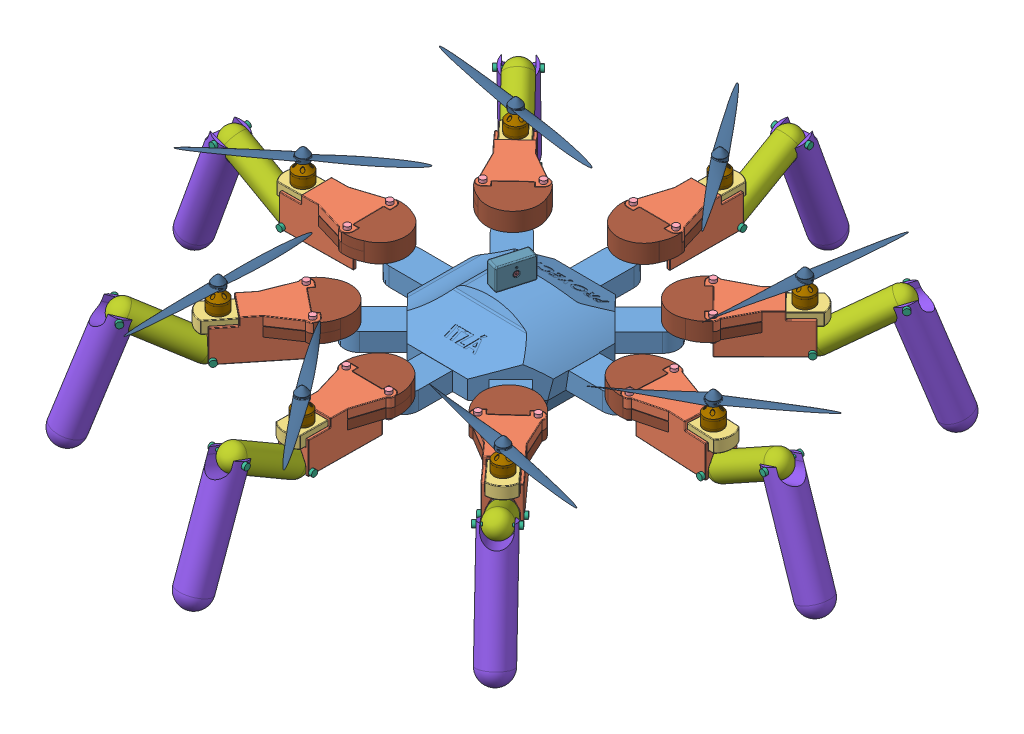
SolidWorks assembly Ensamblaje1, configuration Predeterminado. Lengths in mm.
Overall size (1097.39 246.99 1093.05).
121 component instances, 14 part files, 23 mates.
Components (placement in the parent):
- Cuerpo-1: Cuerpo [Predeterminado] at (-9.0691 -13.0593 180.3619) size (400 129.05 400)
- Sistema de brazo V2-1: Sistema de brazo V2 [Predeterminado] at (128.9081 16.0029 481.489) x (-0.009594 0 0.999954) z (-0.999954 0 -0.009594) size (372.38 235.23 205.09)
  - Brazo1-1: Brazo1 [Predeterminado] at (-6.6953 0.9378 140) size (130.88 65.06 90)
  - Brazo2-1: Brazo2 [Predeterminado] at (-20.6953 5.9378 140) size (180.03 20 40)
  - UnionB1Cuerpo-1: UnionB1Cuerpo [Predeterminado] at (-66.6953 15.9378 105) x (0 1 0) z (0 0 1) size (40 10 10)
  - UnionB1Cuerpo-2: UnionB1Cuerpo [Predeterminado] at (-66.6953 15.9378 175) x (0 1 0) z (-0.093327 0 0.995636) size (40 10 10)
  - TornilloSinFin-1: TornilloSinFin [Predeterminado] at (-26.6953 14.2204 138.1832) x (-1 0 0) z (0 0.686954 0.726701) size (180.05 11.57 10.06)
  - UnionB1P1-1: UnionB1P1 [Predeterminado] at (48.3047 -29.0622 140) x (0 0 -1) z (0.999335 0.036466 0) size (60 10 10)
  - Pierna1V2-1: Pierna1V2 [Predeterminado] at (165.0941 38.3661 140) x (-0.866025 -0.5 0) z (0 0 1) size (150 40 40)
  - Pierna2V2-2: Pierna2V2 [Predeterminado] at (209.6756 -114.1116 140) x (-0.33546 0.942054 0) z (0 0 1) size (200 50 50)
  - UnionB1P1-2: UnionB1P1 [Predeterminado] at (157.0358 33.7137 140) x (0 0 1) z (0.770088 -0.637938 0) size (60 10 10)
  - Motor-1: Motor [Predeterminado] at (39.3047 35.1507 140) x (0.664179 0 0.747574) z (-0.747574 0 0.664179) size (30.15 36.5 30.15)
  - Helise-1: Helise [Predeterminado] at (39.3047 61.4393 140) x (0.608985 0 0.793182) z (-0.793182 0 0.608985) size (28.24 20.07 300)
  - Pinza-1: Pinza [Predeterminado] at (-75.6905 0.9378 140) size (116.44 30 90.88)
- Sistema de brazo V2-2: Sistema de brazo V2 [Predeterminado] at (301.8779 16.0029 303.7493) x (0.668212 0 0.743971) z (-0.743971 0 0.668212) size (372.38 235.23 205.09)
  - Brazo1-1: Brazo1 [Predeterminado] at (-6.6953 0.9378 140) size (130.88 65.06 90)
  - Brazo2-1: Brazo2 [Predeterminado] at (-20.6953 5.9378 140) size (180.03 20 40)
  - UnionB1Cuerpo-1: UnionB1Cuerpo [Predeterminado] at (-66.6953 15.9378 105) x (0 1 0) z (0 0 1) size (40 10 10)
  - UnionB1Cuerpo-2: UnionB1Cuerpo [Predeterminado] at (-66.6953 15.9378 175) x (0 1 0) z (-0.093327 0 0.995636) size (40 10 10)
  - TornilloSinFin-1: TornilloSinFin [Predeterminado] at (-26.6953 14.2204 138.1832) x (-1 0 0) z (0 0.686954 0.726701) size (180.05 11.57 10.06)
  - UnionB1P1-1: UnionB1P1 [Predeterminado] at (48.3047 -29.0622 140) x (0 0 -1) z (0.999335 0.036466 0) size (60 10 10)
  - Pierna1V2-1: Pierna1V2 [Predeterminado] at (165.0941 38.3661 140) x (-0.866025 -0.5 0) z (0 0 1) size (150 40 40)
  - Pierna2V2-2: Pierna2V2 [Predeterminado] at (209.6756 -114.1116 140) x (-0.33546 0.942054 0) z (0 0 1) size (200 50 50)
  - UnionB1P1-2: UnionB1P1 [Predeterminado] at (157.0358 33.7137 140) x (0 0 1) z (0.770088 -0.637938 0) size (60 10 10)
  - Motor-1: Motor [Predeterminado] at (39.3047 35.1507 140) x (0.664179 0 0.747574) z (-0.747574 0 0.664179) size (30.15 36.5 30.15)
  - Helise-1: Helise [Predeterminado] at (39.3047 61.4393 140) x (0.608985 0 0.793182) z (-0.793182 0 0.608985) size (28.24 20.07 300)
  - Pinza-1: Pinza [Predeterminado] at (-75.6905 0.9378 140) size (116.44 30 90.88)
- Sistema de brazo V2-3: Sistema de brazo V2 [Predeterminado] at (297.6452 16.0029 47.3589) x (0.998722 0 0.050534) z (-0.050534 0 0.998722) size (372.38 235.23 205.09)
  - Brazo1-1: Brazo1 [Predeterminado] at (-6.6953 0.9378 140) size (130.88 65.06 90)
  - Brazo2-1: Brazo2 [Predeterminado] at (-20.6953 5.9378 140) size (180.03 20 40)
  - UnionB1Cuerpo-1: UnionB1Cuerpo [Predeterminado] at (-66.6953 15.9378 105) x (0 1 0) z (0 0 1) size (40 10 10)
  - UnionB1Cuerpo-2: UnionB1Cuerpo [Predeterminado] at (-66.6953 15.9378 175) x (0 1 0) z (-0.093327 0 0.995636) size (40 10 10)
  - TornilloSinFin-1: TornilloSinFin [Predeterminado] at (-26.6953 14.2204 138.1832) x (-1 0 0) z (0 0.686954 0.726701) size (180.05 11.57 10.06)
  - UnionB1P1-1: UnionB1P1 [Predeterminado] at (48.3047 -29.0622 140) x (0 0 -1) z (0.999335 0.036466 0) size (60 10 10)
  - Pierna1V2-1: Pierna1V2 [Predeterminado] at (165.0941 38.3661 140) x (-0.866025 -0.5 0) z (0 0 1) size (150 40 40)
  - Pierna2V2-2: Pierna2V2 [Predeterminado] at (209.6756 -114.1116 140) x (-0.33546 0.942054 0) z (0 0 1) size (200 50 50)
  - UnionB1P1-2: UnionB1P1 [Predeterminado] at (157.0358 33.7137 140) x (0 0 1) z (0.770088 -0.637938 0) size (60 10 10)
  - Motor-1: Motor [Predeterminado] at (39.3047 35.1507 140) x (0.664179 0 0.747574) z (-0.747574 0 0.664179) size (30.15 36.5 30.15)
  - Helise-1: Helise [Predeterminado] at (39.3047 61.4393 140) x (0.608985 0 0.793182) z (-0.793182 0 0.608985) size (28.24 20.07 300)
  - Pinza-1: Pinza [Predeterminado] at (-75.6905 0.9378 140) size (116.44 30 90.88)
- Sistema de brazo V2-4: Sistema de brazo V2 [Predeterminado] at (105.4375 16.0029 -130.0624) x (0.710551 0 -0.703646) z (0.703646 0 0.710551) size (372.38 235.23 205.09)
  - Brazo1-1: Brazo1 [Predeterminado] at (-6.6953 0.9378 140) size (130.88 65.06 90)
  - Brazo2-1: Brazo2 [Predeterminado] at (-20.6953 5.9378 140) size (180.03 20 40)
  - UnionB1Cuerpo-1: UnionB1Cuerpo [Predeterminado] at (-66.6953 15.9378 105) x (0 1 0) z (0 0 1) size (40 10 10)
  - UnionB1Cuerpo-2: UnionB1Cuerpo [Predeterminado] at (-66.6953 15.9378 175) x (0 1 0) z (-0.093327 0 0.995636) size (40 10 10)
  - TornilloSinFin-1: TornilloSinFin [Predeterminado] at (-26.6953 14.2204 138.1832) x (-1 0 0) z (0 0.686954 0.726701) size (180.05 11.57 10.06)
  - UnionB1P1-1: UnionB1P1 [Predeterminado] at (48.3047 -29.0622 140) x (0 0 -1) z (0.999335 0.036466 0) size (60 10 10)
  - Pierna1V2-1: Pierna1V2 [Predeterminado] at (165.0941 38.3661 140) x (-0.866025 -0.5 0) z (0 0 1) size (150 40 40)
  - Pierna2V2-2: Pierna2V2 [Predeterminado] at (209.6756 -114.1116 140) x (-0.33546 0.942054 0) z (0 0 1) size (200 50 50)
  - UnionB1P1-2: UnionB1P1 [Predeterminado] at (157.0358 33.7137 140) x (0 0 1) z (0.770088 -0.637938 0) size (60 10 10)
  - Motor-1: Motor [Predeterminado] at (39.3047 35.1507 140) x (0.664179 0 0.747574) z (-0.747574 0 0.664179) size (30.15 36.5 30.15)
  - Helise-1: Helise [Predeterminado] at (39.3047 61.4393 140) x (0.608985 0 0.793182) z (-0.793182 0 0.608985) size (28.24 20.07 300)
  - Pinza-1: Pinza [Predeterminado] at (-75.6905 0.9378 140) size (116.44 30 90.88)
- Sistema de brazo V2-5: Sistema de brazo V2 [Predeterminado] at (-147.6038 16.0029 -120.1096) x (0.004882 0 -0.999988) z (0.999988 0 0.004882) size (372.38 235.23 205.09)
  - Brazo1-1: Brazo1 [Predeterminado] at (-6.6953 0.9378 140) size (130.88 65.06 90)
  - Brazo2-1: Brazo2 [Predeterminado] at (-20.6953 5.9378 140) size (180.03 20 40)
  - UnionB1Cuerpo-1: UnionB1Cuerpo [Predeterminado] at (-66.6953 15.9378 105) x (0 1 0) z (0 0 1) size (40 10 10)
  - UnionB1Cuerpo-2: UnionB1Cuerpo [Predeterminado] at (-66.6953 15.9378 175) x (0 1 0) z (-0.093327 0 0.995636) size (40 10 10)
  - TornilloSinFin-1: TornilloSinFin [Predeterminado] at (-26.6953 14.2204 138.1832) x (-1 0 0) z (0 0.686954 0.726701) size (180.05 11.57 10.06)
  - UnionB1P1-1: UnionB1P1 [Predeterminado] at (48.3047 -29.0622 140) x (0 0 -1) z (0.999335 0.036466 0) size (60 10 10)
  - Pierna1V2-1: Pierna1V2 [Predeterminado] at (165.0941 38.3661 140) x (-0.866025 -0.5 0) z (0 0 1) size (150 40 40)
  - Pierna2V2-2: Pierna2V2 [Predeterminado] at (209.6756 -114.1116 140) x (-0.33546 0.942054 0) z (0 0 1) size (200 50 50)
  - UnionB1P1-2: UnionB1P1 [Predeterminado] at (157.0358 33.7137 140) x (0 0 1) z (0.770088 -0.637938 0) size (60 10 10)
  - Motor-1: Motor [Predeterminado] at (39.3047 35.1507 140) x (0.664179 0 0.747574) z (-0.747574 0 0.664179) size (30.15 36.5 30.15)
  - Helise-1: Helise [Predeterminado] at (39.3047 61.4393 140) x (0.608985 0 0.793182) z (-0.793182 0 0.608985) size (28.24 20.07 300)
  - Pinza-1: Pinza [Predeterminado] at (-75.6905 0.9378 140) size (116.44 30 90.88)
- Sistema de brazo V2-6: Sistema de brazo V2 [Predeterminado] at (-319.7933 16.0029 61.6784) x (-0.687171 0 -0.726496) z (0.726496 0 -0.687171) size (372.38 235.23 205.09)
  - Brazo1-1: Brazo1 [Predeterminado] at (-6.6953 0.9378 140) size (130.88 65.06 90)
  - Brazo2-1: Brazo2 [Predeterminado] at (-20.6953 5.9378 140) size (180.03 20 40)
  - UnionB1Cuerpo-1: UnionB1Cuerpo [Predeterminado] at (-66.6953 15.9378 105) x (0 1 0) z (0 0 1) size (40 10 10)
  - UnionB1Cuerpo-2: UnionB1Cuerpo [Predeterminado] at (-66.6953 15.9378 175) x (0 1 0) z (-0.093327 0 0.995636) size (40 10 10)
  - TornilloSinFin-1: TornilloSinFin [Predeterminado] at (-26.6953 14.2204 138.1832) x (-1 0 0) z (0 0.686954 0.726701) size (180.05 11.57 10.06)
  - UnionB1P1-1: UnionB1P1 [Predeterminado] at (48.3047 -29.0622 140) x (0 0 -1) z (0.999335 0.036466 0) size (60 10 10)
  - Pierna1V2-1: Pierna1V2 [Predeterminado] at (165.0941 38.3661 140) x (-0.866025 -0.5 0) z (0 0 1) size (150 40 40)
  - Pierna2V2-2: Pierna2V2 [Predeterminado] at (209.6756 -114.1116 140) x (-0.33546 0.942054 0) z (0 0 1) size (200 50 50)
  - UnionB1P1-2: UnionB1P1 [Predeterminado] at (157.0358 33.7137 140) x (0 0 1) z (0.770088 -0.637938 0) size (60 10 10)
  - Motor-1: Motor [Predeterminado] at (39.3047 35.1507 140) x (0.664179 0 0.747574) z (-0.747574 0 0.664179) size (30.15 36.5 30.15)
  - Helise-1: Helise [Predeterminado] at (39.3047 61.4393 140) x (0.608985 0 0.793182) z (-0.793182 0 0.608985) size (28.24 20.07 300)
  - Pinza-1: Pinza [Predeterminado] at (-75.6905 0.9378 140) size (116.44 30 90.88)
- Sistema de brazo V2-7: Sistema de brazo V2 [Predeterminado] at (-103.2609 16.0029 487.937) x (-0.627162 0 0.778889) z (-0.778889 0 -0.627162) size (372.38 235.23 205.09)
  - Brazo1-1: Brazo1 [Predeterminado] at (-6.6953 0.9378 140) size (130.88 65.06 90)
  - Brazo2-1: Brazo2 [Predeterminado] at (-20.6953 5.9378 140) size (180.03 20 40)
  - UnionB1Cuerpo-1: UnionB1Cuerpo [Predeterminado] at (-66.6953 15.9378 105) x (0 1 0) z (0 0 1) size (40 10 10)
  - UnionB1Cuerpo-2: UnionB1Cuerpo [Predeterminado] at (-66.6953 15.9378 175) x (0 1 0) z (-0.093327 0 0.995636) size (40 10 10)
  - TornilloSinFin-1: TornilloSinFin [Predeterminado] at (-26.6953 14.2204 138.1832) x (-1 0 0) z (0 0.686954 0.726701) size (180.05 11.57 10.06)
  - UnionB1P1-1: UnionB1P1 [Predeterminado] at (48.3047 -29.0622 140) x (0 0 -1) z (0.999335 0.036466 0) size (60 10 10)
  - Pierna1V2-1: Pierna1V2 [Predeterminado] at (165.0941 38.3661 140) x (-0.866025 -0.5 0) z (0 0 1) size (150 40 40)
  - Pierna2V2-2: Pierna2V2 [Predeterminado] at (209.6756 -114.1116 140) x (-0.33546 0.942054 0) z (0 0 1) size (200 50 50)
  - UnionB1P1-2: UnionB1P1 [Predeterminado] at (157.0358 33.7137 140) x (0 0 1) z (0.770088 -0.637938 0) size (60 10 10)
  - Motor-1: Motor [Predeterminado] at (39.3047 35.1507 140) x (0.664179 0 0.747574) z (-0.747574 0 0.664179) size (30.15 36.5 30.15)
  - Helise-1: Helise [Predeterminado] at (39.3047 61.4393 140) x (0.608985 0 0.793182) z (-0.793182 0 0.608985) size (28.24 20.07 300)
  - Pinza-1: Pinza [Predeterminado] at (-75.6905 0.9378 140) size (116.44 30 90.88)
- Sistema de brazo V2-8: Sistema de brazo V2 [Predeterminado] at (-307.3367 16.0029 320.7319) x (-0.999941 0 0.010821) z (-0.010821 0 -0.999941) size (372.38 235.23 205.09)
  - Brazo1-1: Brazo1 [Predeterminado] at (-6.6953 0.9378 140) size (130.88 65.06 90)
  - Brazo2-1: Brazo2 [Predeterminado] at (-20.6953 5.9378 140) size (180.03 20 40)
  - UnionB1Cuerpo-1: UnionB1Cuerpo [Predeterminado] at (-66.6953 15.9378 105) x (0 1 0) z (0 0 1) size (40 10 10)
  - UnionB1Cuerpo-2: UnionB1Cuerpo [Predeterminado] at (-66.6953 15.9378 175) x (0 1 0) z (-0.093327 0 0.995636) size (40 10 10)
  - TornilloSinFin-1: TornilloSinFin [Predeterminado] at (-26.6953 14.2204 138.1832) x (-1 0 0) z (0 0.686954 0.726701) size (180.05 11.57 10.06)
  - UnionB1P1-1: UnionB1P1 [Predeterminado] at (48.3047 -29.0622 140) x (0 0 -1) z (0.999335 0.036466 0) size (60 10 10)
  - Pierna1V2-1: Pierna1V2 [Predeterminado] at (165.0941 38.3661 140) x (-0.866025 -0.5 0) z (0 0 1) size (150 40 40)
  - Pierna2V2-2: Pierna2V2 [Predeterminado] at (209.6756 -114.1116 140) x (-0.33546 0.942054 0) z (0 0 1) size (200 50 50)
  - UnionB1P1-2: UnionB1P1 [Predeterminado] at (157.0358 33.7137 140) x (0 0 1) z (0.770088 -0.637938 0) size (60 10 10)
  - Motor-1: Motor [Predeterminado] at (39.3047 35.1507 140) x (0.664179 0 0.747574) z (-0.747574 0 0.664179) size (30.15 36.5 30.15)
  - Helise-1: Helise [Predeterminado] at (39.3047 61.4393 140) x (0.608985 0 0.793182) z (-0.793182 0 0.608985) size (28.24 20.07 300)
  - Pinza-1: Pinza [Predeterminado] at (-75.6905 0.9378 140) size (116.44 30 90.88)
- Conectorde ensambles-1: Conectorde ensambles [Predeterminado] at (-191.567 16.9407 179.4709) size (5 20 5)
- Conectorde ensambles-2: Conectorde ensambles [Predeterminado] at (-138.7446 16.9407 308.7773) size (5 20 5)
- Conectorde ensambles-3: Conectorde ensambles [Predeterminado] at (-9.9601 16.9407 362.8597) size (5 20 5)
- Conectorde ensambles-4: Conectorde ensambles [Predeterminado] at (119.3463 16.9407 310.0374) size (5 20 5)
- Conectorde ensambles-5: Conectorde ensambles [Predeterminado] at (120.6064 16.9407 51.9465) size (5 20 5)
- Conectorde ensambles-6: Conectorde ensambles [Predeterminado] at (173.4287 16.9407 181.2529) size (5 20 5)
- Conectorde ensambles-7: Conectorde ensambles [Predeterminado] at (-8.1781 16.9407 -2.136) size (5 20 5)
- Conectorde ensambles-8: Conectorde ensambles [Predeterminado] at (-137.4845 16.9407 50.6864) size (5 20 5)
- Conectorde ensambles-9: Conectorde ensambles [Predeterminado] at (-9.0691 75.9407 180.3619) x (0.125232 0 -0.992127) z (0.992127 0 0.125232) size (5 20 5)
- Conectorde ensambles-10: Conectorde ensambles [Predeterminado] at (-32.2248 -55.0578 180.3619) x (0.999405 0 0.034483) z (-0.034483 0 0.999405) size (5 20 5)
- Camara-1: Camara [Predeterminado] at (-93.6993 -69.572 219.4602) x (-0.88876 0 -0.458373) z (0.458355 -0.008727 -0.888726) size (56 36.17 20.31)
  - Camara-1: Camara [Predeterminado] at (-38.4113 -4.107 68.8002) x (1 0 0) z (0 -0.999962 0.008727) size (30 3.56 30)
  - GoProCamara-1: GoProCamara [Predeterminado] at (-38.4113 -3.0252 52.7902) x (1 0 0) z (0 0.008727 0.999962) size (56 36 20)
- Camara-2: Camara [Predeterminado] at (-79.6672 82.9549 198.354) x (-0.275025 0 0.961437) z (0.9614 0.008727 0.275015) size (56 36.17 20.31)
  - Camara-1: Camara [Predeterminado] at (-38.4113 -4.107 68.8002) x (1 0 0) z (0 -0.999962 0.008727) size (30 3.56 30)
  - GoProCamara-1: GoProCamara [Predeterminado] at (-38.4113 -3.0252 52.7902) x (1 0 0) z (0 0.008727 0.999962) size (56 36 20)
Mates (geometry in assembly coordinates):
- Coincidente2: coincident aligned: circle of Cuerpo-1; circle of Conectorde ensambles-1
- Coincidente1: coincident anti-aligned: circle of Sistema de brazo V2-8/Pinza-1; circle of Conectorde ensambles-1
- Coincidente3: coincident anti-aligned: circle of Sistema de brazo V2-7/Pinza-1; circle of Conectorde ensambles-2
- Coincidente4: coincident aligned: circle of Cuerpo-1; circle of Conectorde ensambles-2
- Coincidente5: coincident anti-aligned: circle of Sistema de brazo V2-1/Pinza-1; circle of Conectorde ensambles-3
- Coincidente6: coincident aligned: circle of Cuerpo-1; circle of Conectorde ensambles-3
- Coincidente7: coincident anti-aligned: circle of Sistema de brazo V2-2/Pinza-1; circle of Conectorde ensambles-4
- Coincidente8: coincident aligned: circle of Cuerpo-1; circle of Conectorde ensambles-4
- Coincidente9: coincident aligned: circle of Cuerpo-1; circle of Conectorde ensambles-6
- Coincidente10: coincident aligned: circle of Cuerpo-1; circle of Conectorde ensambles-5
- Coincidente11: coincident aligned: circle of Cuerpo-1; circle of Conectorde ensambles-7
- Coincidente12: coincident aligned: circle of Cuerpo-1; circle of Conectorde ensambles-8
- Coincidente13: coincident anti-aligned: circle of Sistema de brazo V2-3/Pinza-1; circle of Conectorde ensambles-6
- Coincidente14: coincident anti-aligned: circle of Sistema de brazo V2-4/Pinza-1; circle of Conectorde ensambles-5
- Coincidente15: coincident anti-aligned: circle of Sistema de brazo V2-5/Pinza-1; circle of Conectorde ensambles-7
- Coincidente16: coincident anti-aligned: circle of Sistema de brazo V2-6/Pinza-1; circle of Conectorde ensambles-8
- Concéntrica1: concentric aligned: cylinder of Cuerpo-1 through (-9.0691 76.9407 180.3619) axis (0 -1 0) radius 2.5; cylinder of Conectorde ensambles-9 through (-9.0691 85.9407 180.3619) axis (0 -1 0) radius 2.5
- Coincidente17: coincident aligned: circle of Cuerpo-1; circle of Conectorde ensambles-9
- Coincidente19: coincident aligned: circle of Cuerpo-1; circle of Conectorde ensambles-10
- Concéntrica2: concentric aligned: cylinder of Conectorde ensambles-9 through (-9.0691 85.9407 180.3619) axis (0 -1 0) radius 2.5; cylinder of Camara-2/GoProCamara-1 through (-9.0691 69.4407 180.3619) axis (0 -1 0) radius 2.5
- Coincidente23: coincident aligned: plane of Conectorde ensambles-10 through (-32.2248 -55.0578 180.3619) normal (0 1 0); circle of Camara-1/GoProCamara-1
- Concéntrica3: concentric anti-aligned: cylinder of Conectorde ensambles-10 through (-32.2248 -45.0578 180.3619) axis (0 -1 0) radius 2.5; cylinder of Camara-1/GoProCamara-1 through (-32.2248 -56.0578 180.3619) axis (0 1 0) radius 2.5
- Coincidente24: coincident anti-aligned: plane of Conectorde ensambles-9 through (-9.0691 69.4407 180.3619) normal (0 1 0); circle of Camara-2/GoProCamara-1
